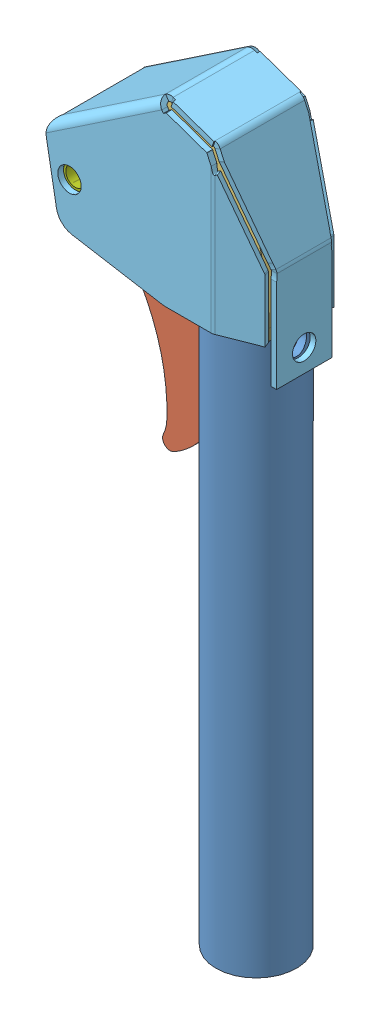
SolidWorks assembly A.01.00 - Газулька, configuration 00. Lengths in mm.
Overall size (103.18 265.64 26.01).
10 component instances, 8 part files, 14 mates.
Components (placement in the parent):
- A.01.02 - Труба основа-1: A.01.02 - Труба основа [--] at origin size (21.3 150 21.3) (hidden)
- A.01.01.02 - Курок (6мм)-1: A.01.01.02 - Курок (6мм) [--] at (-36.3091 13.3669 0) x (0.932086 0.362238 0) z (0 0 1) size (51.69 73.77 6)
- A.01.01.01.02 - Опора курка (4мм)-1: A.01.01.01.02 - Опора курка (4мм) [--] at (0 0 3.25) size (56.96 43.45 4)
- A.01.01.01.01 - Вставка в трубу-1: A.01.01.01.01 - Вставка в трубу [--] at origin size (17.24 50 17.3)
- A.01.03 - Кожух (1_5мм)-1: A.01.03 - Кожух (1_5мм) [--] at origin size (56.43 56.76 26.01)
- Ось курка-1: Ось курка [--] at (-36.3091 13.3669 7.25) size (13 13 23) (hidden)
- A.01.01.03.00 - Ось курка-2: A.01.01.03.00 - Ось курка [00] at (-36.3091 13.3669 7.25) size (13 13 23)
  - A.01.01.03.01 - Ось-1: A.01.01.03.01 - Ось [--] at origin size (13 13 23)
  - A.01.01.03.02 - Шайба оси-1: A.01.01.03.02 - Шайба оси [--] at origin size (13 13 4.25)
- A.01.01.01.02 - Опора курка (4мм)-2: A.01.01.01.02 - Опора курка (4мм) [--] at (0 0 -7.25) size (56.96 43.45 4)
Mates (geometry in assembly coordinates):
- Совпадение1: coincident: point of A.01.01.02 - Курок (6мм)-1; point of assembly
- Совпадение2: coincident: plane of A.01.01.02 - Курок (6мм)-1 through (-36.3091 13.3669 0) normal (0 0 1); line of assembly
- Совпадение3: coincident: plane of A.01.01.02 - Курок (6мм)-1 through (-36.3091 13.3669 0) normal (0.932086 0.362238 0); line of assembly
- Перпендикулярность1: perpendicular: plane of A.01.01.02 - Курок (6мм)-1 through (-36.3091 13.3669 0) normal (-0.362238 0.932086 0); plane of assembly through (0 0 0) normal (0 0 1)
- Расстояние1: distance = 0.25 mm: plane of A.01.01.01.02 - Опора курка (4мм)-1 through (0 0 3.25) normal (0 0 1); plane of A.01.01.02 - Курок (6мм)-1 through (-19.7449 -43.334 3) normal (0 0 1)
- Совпадение4: coincident: plane of A.01.01.01.02 - Опора курка (4мм)-1 through (0 0 3.25) normal (0 1 0); plane of assembly through (0 0 0) normal (0 1 0)
- Совпадение5: coincident: plane of A.01.01.01.02 - Опора курка (4мм)-1 through (0 0 3.25) normal (1 0 0); plane of assembly through (0 0 0) normal (1 0 0)
- Совпадение6: coordinate: unknown of ?
- Совпадение7: coincident: plane of A.01.01.01.02 - Опора курка (4мм)-1 through (-52.2585 0 7.25) normal (0 0 1); plane of Ось курка-1 through (-36.3091 13.3669 7.25) normal (0 0 1)
- Параллельность1: parallel: plane of Ось курка-1 through (-36.3091 13.3669 7.25) normal (0 1 0); plane of assembly through (0 0 0) normal (0 1 0)
- Совпадение8: coincident: plane of ? through (-36.3091 13.3669 7.25) normal (0 1 0)
- Совпадение9: coincident: plane of ? through (-36.3091 13.3669 7.25) normal (1 0 0)
- Концентричный1: concentric: cylinder of Ось курка-1 through (-36.3091 13.3669 11.5) axis (0 0 1) radius 2.5; cylinder of A.01.01.03.00 - Ось курка-2/A.01.01.03.01 - Ось-1 through (-36.3091 13.3669 11.5) axis (0 0 1) radius 2.5
- Совпадение10: coincident: plane of A.01.03 - Кожух (1_5мм)-1 through (0 0 11.5) normal (0 0 -1); plane of A.01.01.03.00 - Ось курка-2/A.01.01.03.01 - Ось-1 through (-36.3091 13.3669 11.5) normal (0 0 1)
